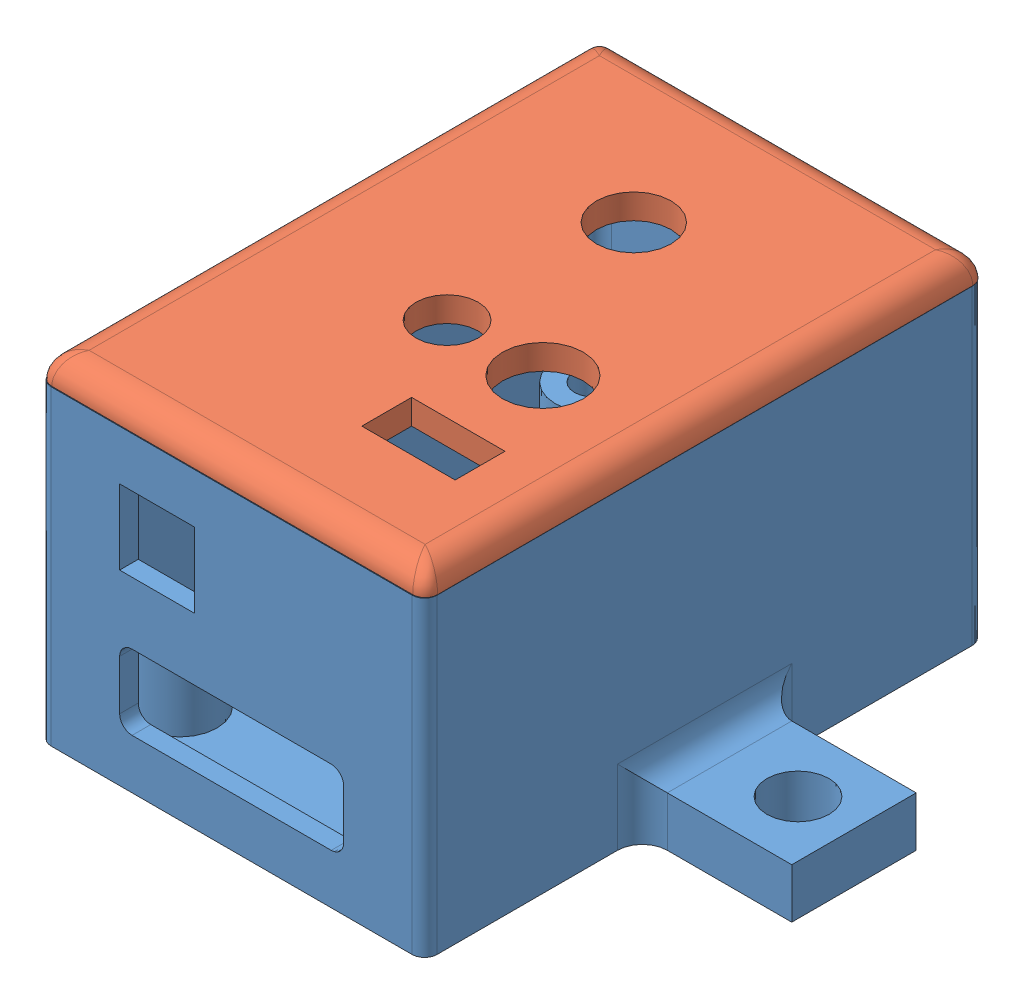
SolidWorks assembly Assem1, configuration Default. Lengths in mm.
Overall size (55 27 45.06).
2 component instances, 2 part files, 0 mates.
Components (placement in the parent):
- Box bottom v2-1: Box bottom v2 [Default] at (21.9327 18.4476 39.9514) size (55 25 45)
- Box lid v2-2: Box lid v2 [Default] at (21.9193 43.4506 39.8901) size (31 4 45)
